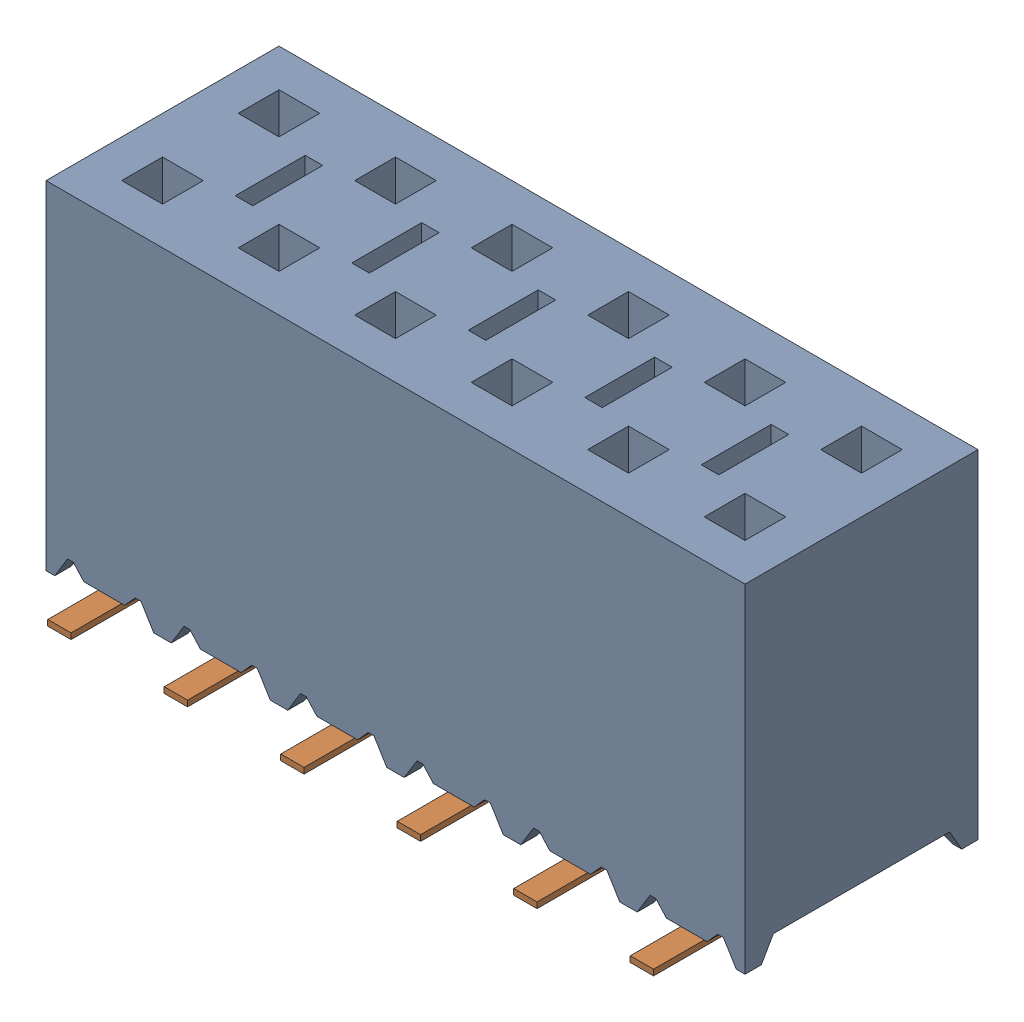
SolidWorks assembly SSM-106-F-DV.step, configuration Default. Lengths in mm.
Overall size (15.24 7.42 7.04).
2 component instances, 2 part files, 0 mates.
Components (placement in the parent):
- _SSM-106-F-DV_body.step-1: _SSM-106-F-DV_body.step [Default] at origin size (15.24 7.37 5.08)
- _C-137-016.step-1: _C-137-016.step [Default] at (0 -0.0508 0) size (13.21 1.91 7.04)
